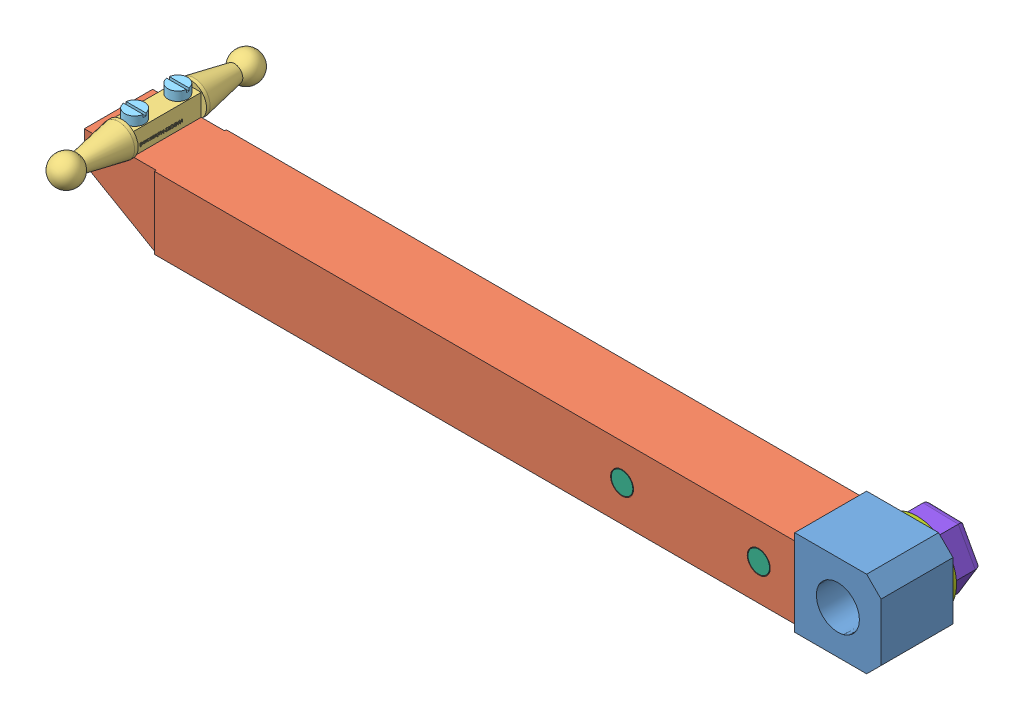
SolidWorks assembly Bras, configuration Défaut. Lengths in mm.
Overall size (260.71 64.17 58).
10 component instances, 8 part files, 22 mates.
Components (placement in the parent):
- Pièce2_support_bras-1: Pièce2_support_bras [Défaut] at origin size (78 24 20)
- Pièce3_Bras-1: Pièce3_Bras [Défaut] at (-101 10 10) x (-1 0 0) z (0 -1 0) size (198 20 20)
- Pièce2_Articulation-1: Pièce2_Articulation [Défaut] at (-199.5 13 10) x (0 0 1) z (1 0 0) size (58 9 9)
- Pièce3_EcrouBras-1: Pièce3_EcrouBras [Défaut] at (-199.5 5.5 10) x (0 0 -1) z (0 1 0) size (17 8 3)
- Pièce5_ViceTcyM3_10-1: Pièce5_ViceTcyM3_10 [Défaut] at (-199.5 18.5 4) x (-1 0 0) z (0 -1 0) size (5.5 5.5 12.5)
- Pièce5_ViceTcyM3_10-2: Pièce5_ViceTcyM3_10 [Défaut] at (-199.5 18.5 16) x (-1 0 0) z (0 -1 0) size (5.5 5.5 12.5)
- Pièce3_VisBras-1: Pièce3_VisBras [Défaut] at (-60 0 0) size (6 6 20)
- Pièce3_VisBras-2: Pièce3_VisBras [Défaut] at (-22 0 0) size (6 6 20)
- Pièce1_Rendelle-1: Pièce1_Rendelle [Défaut] x (-0.923728 -0.383049 0) z (0 0 -1) size (22 22 2)
- Pièce2_EcrouBras-1: Pièce2_EcrouBras [Défaut] at (0 0 -10.4) x (-0.021598 -0.999767 0) z (0 0 -1) size (17 19.63 8.4)
Mates (geometry in assembly coordinates):
- Coïncidente1: coincident anti-aligned: plane of Pièce3_Bras-1 through (-101 8.5 10) normal (0 -1 0); plane of Pièce3_EcrouBras-1 through (-199.5 8.5 10) normal (0 1 0)
- Coaxiale3: concentric anti-aligned: cylinder of Pièce3_Bras-1 through (-199.5 -14 4) axis (0 1 0) radius 1.6; cylinder of Pièce3_EcrouBras-1 through (-199.5 8.5 4) axis (0 -1 0) radius 1.5
- Coaxiale4: concentric anti-aligned: cylinder of Pièce3_Bras-1 through (-199.5 -14 16) axis (0 1 0) radius 1.6; cylinder of Pièce3_EcrouBras-1 through (-199.5 8.5 16) axis (0 -1 0) radius 1.5
- Coaxiale5: concentric anti-aligned: cylinder of Pièce3_Bras-1 through (-199.5 -14 4) axis (0 1 0) radius 1.6; cylinder of Pièce2_Articulation-1 through (-199.5 19.5 4) axis (0 -1 0) radius 1.6
- Coaxiale6: concentric anti-aligned: cylinder of Pièce3_Bras-1 through (-199.5 -14 16) axis (0 1 0) radius 1.6; cylinder of Pièce2_Articulation-1 through (-199.5 19.5 16) axis (0 -1 0) radius 1.6
- Coïncidente2: coincident anti-aligned: plane of Pièce3_Bras-1 through (-101 10 10) normal (0 1 0); plane of Pièce2_Articulation-1 through (-202.5 10 0.5) normal (0 -1 0)
- Coaxiale7: concentric anti-aligned: cylinder of Pièce3_EcrouBras-1 through (-199.5 8.5 4) axis (0 -1 0) radius 1.5; cylinder of Pièce5_ViceTcyM3_10-1 through (-199.5 6 4) axis (0 1 0) radius 1.5
- Coïncidente3: coincident anti-aligned: plane of Pièce2_Articulation-1 through (-202.5 16 0.5) normal (0 1 0); plane of Pièce5_ViceTcyM3_10-1 through (-199.5 16 4) normal (0 -1 0)
- Coaxiale8: concentric anti-aligned: cylinder of Pièce2_Articulation-1 through (-199.5 19.5 16) axis (0 -1 0) radius 1.6; cylinder of Pièce5_ViceTcyM3_10-2 through (-199.5 6 16) axis (0 1 0) radius 1.5
- Coïncidente4: coincident anti-aligned: plane of Pièce2_Articulation-1 through (-202.5 16 0.5) normal (0 1 0); plane of Pièce5_ViceTcyM3_10-2 through (-199.5 16 16) normal (0 -1 0)
- Coaxiale9: concentric anti-aligned: cylinder of Pièce2_support_bras-1 through (-60 0 20) axis (0 0 -1) radius 3; cylinder of Pièce3_Bras-1 through (-60 0 -14) axis (0 0 1) radius 3.2
- Coaxiale10: concentric anti-aligned: cylinder of Pièce2_support_bras-1 through (-22 0 20) axis (0 0 -1) radius 3; cylinder of Pièce3_Bras-1 through (-22 0 -14) axis (0 0 1) radius 3.2
- Coïncidente5: coincident anti-aligned: plane of Pièce2_support_bras-1 through (0 0 18.5) normal (0 0 1); plane of Pièce3_Bras-1 through (-190 8.5 18.5) normal (0 0 -1)
- Coaxiale11: concentric aligned: cylinder of Pièce2_support_bras-1 through (-60 0 20) axis (0 0 -1) radius 3; cylinder of Pièce3_VisBras-1 through (-60 0 20) axis (0 0 -1) radius 3
- Coïncidente6: coincident aligned: plane of Pièce3_Bras-1 through (-101 -10 0) normal (0 0 -1); plane of Pièce3_VisBras-1 through (-60 0 0) normal (0 0 -1)
- Coaxiale12: concentric aligned: cylinder of Pièce2_support_bras-1 through (-22 0 20) axis (0 0 -1) radius 3; cylinder of Pièce3_VisBras-2 through (-22 0 20) axis (0 0 -1) radius 3
- Coïncidente7: coincident aligned: plane of Pièce3_Bras-1 through (-101 -10 0) normal (0 0 -1); plane of Pièce3_VisBras-2 through (-22 0 0) normal (0 0 -1)
- Coïncidente8: coincident anti-aligned: plane of Pièce2_support_bras-1 through (0 0 0) normal (0 0 -1); plane of Pièce1_Rendelle-1 through (0 0 0) normal (0 0 1)
- Coaxiale13: concentric anti-aligned: cylinder of Pièce2_support_bras-1 through (0 0 20) axis (0 0 -1) radius 6; cylinder of Pièce1_Rendelle-1 through (0 0 -2) axis (0 0 1) radius 5
- Coïncidente9: coincident aligned: plane of Pièce1_Rendelle-1 through (0 0 -2) normal (0 0 -1); plane of Pièce2_EcrouBras-1 through (0 0 -2) normal (0 0 -1)
- Coaxiale14: concentric anti-aligned: cylinder of Pièce2_support_bras-1 through (0 0 20) axis (0 0 -1) radius 6; cylinder of Pièce2_EcrouBras-1 through (0 0 -2) axis (0 0 1) radius 5
- Coïncidente10: coincident anti-aligned: plane of Pièce1_Rendelle-1 through (0 0 -2) normal (0 0 -1); plane of Pièce2_EcrouBras-1 through (0 0 -2) normal (0 0 1)
